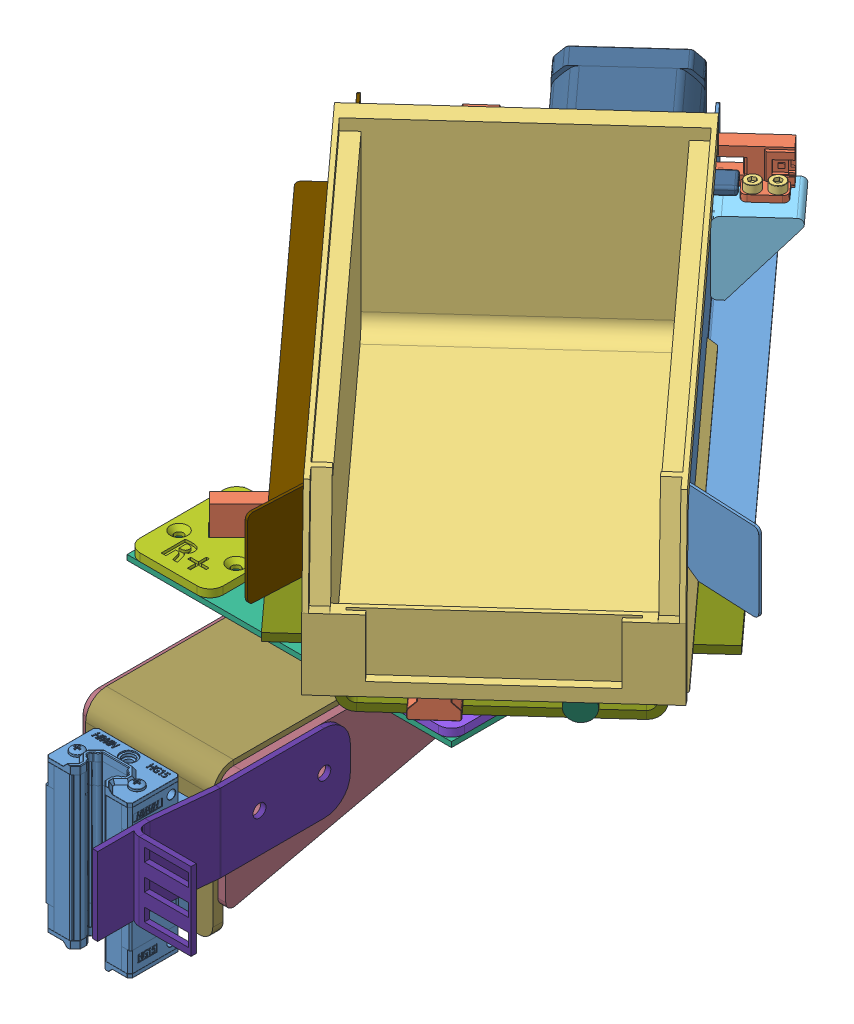
SolidWorks assembly T00003-000-R01, configuration Default. Lengths in mm.
Overall size (264.26 185.95 323.84).
38 component instances, 28 part files, 239 mates.
Components (placement in the parent):
- T00108-E00-R00-3: T00108-E00-R00 [Default] at (157.9488 862.2474 269.7743) x (1 0 0) z (0 1 0) size (34 23.7 61.49)
- T00110-E00-R00-1: T00110-E00-R00 [HGR15R400CE20] at (232.0778 918.7474 206.0743) x (0.739937 0 -0.672676) z (0.672676 0 0.739937) size (15 15 270)
- T00108-E00-R00-4: T00108-E00-R00 [Default] at (95.9442 919.5474 56.3288) x (0.739937 0 -0.672676) z (0.672676 0 0.739937) size (34 23.7 61.49)
- T00148-E00-R00-1: T00148-E00-R00 [Default] at (105.2918 941.2474 117.7314) x (0.739937 0 -0.672676) z (0.672676 0 0.739937) size (104.77 76.2 187.32)
- T00126-000-R00-1: T00126-000-R00 [Default] at (95.9442 950.5474 56.3288) x (0.739937 0 -0.672676) z (0 1 0) size (75 74 94)
- T00127-E00-R00-1: T00127-E00-R00 [DIN 625 - 6002 - 12,SI,NC,12_68] at (157.9488 901.2474 97.7743) x (0 1 0) z (0 0 1) size (9 32 32)
- T00128-0A4-R00-1: T00128-0A4-R00 [Default] at (157.9488 887.7474 97.7743) x (1 0 0) z (0 -1 0) size (25 25 21)
- T00129-E00-R00-1: T00129-E00-R00 [Circlip DIN 471 - 15 x 1.5] at (157.9488 905.9474 97.7743) x (0.837169 0 0.546944) z (0 -1 0) size (17.74 21.49 1.5)
- T00130-0A4-R01-1: T00130-0A4-R01 [Default] at (157.9488 895.7474 97.7743) x (0.672676 0 0.739937) z (0 -1 0) size (90 90 20)
- T00132-E00-R00-4: T00132-E00-R00 [Metric - Spur gear 1M 60T 20PA 9FW ---S60N75H50L42N] at (157.9488 896.7474 97.7743) x (0 1 0) z (0 0 1) size (9 61.95 61.95)
- T00107-E00-R00-1: T00107-E00-R00 [Varsayılan] at (157.9488 879.7474 61.7743) x (-1 0 0) z (0 1 0) size (42 58.5 65.65)
- T00131-E00-R00-2: T00131-E00-R00 [Metric - Spur gear 1M 12T 20PA 8FW ---S12O10H14L5N] at (157.9488 896.7474 61.7743) x (0 1 0) z (0.924225 0 0.381849) size (14 13.61 13.61)
- T00133-0A4-R00-3: T00133-0A4-R00 [Default] at (157.9488 862.2474 237.7743) x (1 0 0) z (0 1 0) size (49 210 57)
- T00134-DXF-R00-1: T00134-DXF-R00 [Default] at (130.4488 892.7474 239.7743) x (0 0 -1) z (-1 0 0) size (155 44.25 3)
- T00134-DXF-R00-2: T00134-DXF-R00 [Default] at (182.4488 892.7474 239.7743) x (0 0 -1) z (-1 0 0) size (155 44.25 3)
- T00105-E00-R00-1: T00105-E00-R00 [Default] at (142.4488 890.7474 46.2743) x (1 0 0) z (0 -1 0) size (6 6 11)
- T00105-E00-R00-2: T00105-E00-R00 [Default] at (173.4488 890.7474 46.2743) x (0.974973 0 -0.222324) z (0 -1 0) size (6 6 11)
- T00105-E00-R00-3: T00105-E00-R00 [Default] at (142.4488 890.7474 77.2743) x (1 0 0) z (0 -1 0) size (6 6 11)
- T00105-E00-R00-4: T00105-E00-R00 [Default] at (173.4488 890.7474 77.2743) x (1 0 0) z (0 -1 0) size (6 6 11)
- T00107-E00-R00-2: T00107-E00-R00 [Varsayılan] at (107.666 933.2474 9.0154) x (-0.739937 0 0.672676) z (0.672676 0 0.739937) size (42 58.5 65.65)
- T00111-E00-R00-1: T00111-E00-R00 [Default] at (270.4537 933.2474 188.0801) x (-0.427706 0.816015 0.388828) z (-0.603799 -0.578031 0.548914) size (10 240 10)
- T00135-DXF-R01-1: T00135-DXF-R01 [Default] at (168.0389 918.7474 108.8734) x (-0.672676 0 -0.739937) z (0.739937 0 -0.672676) size (219 39 131)
- T00136-DXF-R01-1: T00136-DXF-R01 [Default] at (187.4488 877.7474 233.7743) x (0 0 -1) z (1 0 0) size (94.88 30 25)
- T00137-000-R00-1: T00137-000-R00 [gespiegeld] at (182.1991 941.2474 198.0361) x (0.672676 0 0.739937) z (-0.739937 0 0.672676) size (201.93 32 21.92)
- T00138-000-R00-1: T00138-000-R00 [gespiegeld] at (254.7129 941.2474 132.1138) x (0.672676 0 0.739937) z (-0.739937 0 0.672676) size (201.93 32 21.92)
- T00153-E00-R00-4: T00153-E00-R00 [Default] at (161.4127 977.2474 25.0247) x (-0.672676 0 -0.739937) z (0 1 0) size (13 22.4 13.7)
- socket head cap screw_iso-1: socket head cap screw_iso [ISO 4762 M3 x 16 - 16N] at (172.7808 978.7474 24.1502) x (0 -1 0) z (0.997971 0 0.063667) size (19 5.5 5.5)
- hex nut style 1 gradeab_iso-1: hex nut style 1 gradeab_iso [ISO - 4032 - M3 - W - N] at (172.7808 965.2474 24.1502) x (1 0 0) z (0 1 0) size (5.5 6.35 2.4)
- socket head cap screw_iso-2: socket head cap screw_iso [ISO 4762 M3 x 16 - 16N] at (177.9604 978.7474 19.4415) x (0 -1 0) z (0 0 1) size (19 5.5 5.5)
- hex nut style 1 gradeab_iso-3: hex nut style 1 gradeab_iso [ISO - 4032 - M3 - W - N] at (177.9604 965.4397 19.4415) x (0.95019 0 0.311672) z (0 1 0) size (5.5 6.35 2.4)
- T00153-E00-R00-7: T00153-E00-R00 [Default] at (120.7549 900.9974 152.459) x (0.707107 0 0.707107) z (0 1 0) size (13 22.4 13.7)
- T00153-E00-R00-8: T00153-E00-R00 [Default] at (195.1426 900.9974 152.459) x (0.707107 0 -0.707107) z (0 1 0) size (13 22.4 13.7)
- T00168-03D-R00-2: T00168-03D-R00 [Default] at (164.6415 959.2474 31.5496) x (-0.672676 0 -0.739937) z (0.739937 0 -0.672676) size (20 28 25.65)
- T00161-0A4-R00-2: T00161-0A4-R00 [Default] at (157.9488 894.7474 165.2743) size (125 2 45)
- T00164-03D-R00-1: T00164-03D-R00 [Default] at (157.9488 896.7474 165.2743) x (1 0 0) z (0 1 0) size (32 42.2 3)
- T00165-03D-R00-1: T00165-03D-R00 [Default] at (250.9488 896.7474 165.2743) x (1 0 0) z (0 1 0) size (32 42.2 3)
- T00162-03D-R02-1: T00162-03D-R02 [Default] at (191.5826 915.7474 134.7711) x (0.739937 0 -0.672676) z (0 -1 0) size (28 24.69 13.5)
- T00163-03D-R01-1: T00163-03D-R01 [Default] at (159.0073 970.5474 55.084) x (0.739937 0 -0.672676) z (0 1 0) size (38 30 18.2)
Mates (geometry in assembly coordinates):
- Coincident1: coincident: plane of ? through (170.4488 216.5018 364.6743) normal (1 0 0); plane of ? through (170.4488 228.5018 34.6743) normal (-1 0 0)
- Coincident2: coincident: plane of ? through (148.4488 238.5018 364.6743) normal (0 1 0); plane of ? through (170.4488 238.5018 394.6743) normal (0 1 0)
- Coincident3: coincident: plane of ? through (145.4488 216.5018 364.6743) normal (-1 0 0); plane of ? through (145.4488 223.5018 394.6743) normal (1 0 0)
- Coincident4: coincident: plane of ? through (148.4488 213.5018 364.6743) normal (0 -1 0); plane of ? through (142.4488 213.5018 34.6743) normal (0 -1 0)
- Coincident5: coincident: plane of ? through (142.4488 228.5018 404.6743) normal (0 0 1); plane of ? through (170.4488 223.5018 404.6743) normal (0 0 1)
- Width1: width: plane of ? through (142.4488 228.5018 404.6743) normal (0 0 1); plane of ? through (142.4488 228.5018 24.6743) normal (0 0 -1); plane of ? through (148.4488 216.5018 64.6743) normal (0 0 -1); plane of ? through (148.4488 216.5018 364.6743) normal (0 0 1)
- Concentric1: concentric: cylinder of ? through (142.4488 226.0018 394.6743) axis (1 0 0) radius 3.25; cylinder of ? through (157.9488 226.0018 394.6743) axis (-1 0 0) radius 3
- Concentric2: concentric: cylinder of ? through (142.4488 226.0018 34.6743) axis (1 0 0) radius 3.25; cylinder of ? through (157.9488 226.0018 34.6743) axis (-1 0 0) radius 3
- Width2: width: plane of ? through (168.9488 223.0018 34.6743) normal (1 0 0); plane of ? through (146.9488 219.0018 34.6743) normal (-1 0 0); plane of ? through (145.4488 223.5018 394.6743) normal (1 0 0); plane of ? through (170.4488 228.5018 34.6743) normal (-1 0 0)
- Width3: width: plane of ? through (168.9488 223.0127 394.9296) normal (1 0 0); plane of ? through (146.9488 219.0272 395.2699) normal (-1 0 0); plane of ? through (142.4488 223.5018 394.6743) normal (-1 0 0); plane of ? through (173.4488 228.5018 34.6743) normal (1 0 0)
- Tangent1: tangent: cylinder of ? through (157.9488 226.0018 -111.0344) axis (-1 0 0) radius 25; plane of ? through (135.9488 201.0018 1171.0489) normal (0 1 0)
- Tangent2: tangent: cylinder of ? through (157.9488 226.0018 -471.0344) axis (-1 0 0) radius 25; plane of ? through (135.9488 201.0018 1171.0489) normal (0 1 0)
- Width4: width: plane of ? through (173.4488 228.5018 -471.0344) normal (1 0 0); plane of ? through (142.4488 223.5018 -111.0344) normal (-1 0 0); plane of ? through (179.9488 201.0018 1171.0489) normal (-1 0 0); plane of ? through (135.9488 201.0018 1171.0489) normal (1 0 0)
- Width9: width: plane of ? through (172.9488 242.5018 314.4743) normal (1 0 0); plane of ? through (142.9488 242.5018 274.8743) normal (-1 0 0); plane of ? through (142.4488 223.5018 394.6743) normal (-1 0 0); plane of ? through (173.4488 228.5018 34.6743) normal (1 0 0)
- Coincident16: coincident: plane of ? through (148.1488 242.5018 269.6743) normal (0 0 -1); plane of ? through (150.9488 242.5018 269.6743) normal (0 0 1)
- Width10: width: plane of ? through (150.4488 833.0474 258.1086) normal (1 0 0); plane of ? through (165.4488 833.0474 258.1086) normal (-1 0 0); plane of ? through (150.4488 242.5018 258.0086) normal (-1 0 0); plane of ? through (165.4488 242.5018 258.0086) normal (1 0 0)
- Coincident18: coincident: plane of ? through (152.9073 834.5474 254.6743) normal (0 0 1); plane of ? through (162.9488 242.5018 254.6743) normal (0 0 -1)
- Width11: width: plane of ? through (172.9488 242.5018 314.4743) normal (1 0 0); plane of ? through (142.9488 242.5018 274.8743) normal (-1 0 0); plane of ? through (150.4488 242.5018 269.1743) normal (-1 0 0); plane of ? through (165.4488 242.5018 269.1743) normal (1 0 0)
- Coincident23: coincident: plane of T00110-E00-R00-1; plane of ? through (70.8326 930.4131 121.9122) normal (0.01567 0 -0.999877)
- Coincident24: coincident: plane of T00110-E00-R00-1 through (17.7623 933.7474 108.579) normal (0 1 0); plane of ? through (70.8718 933.7474 119.4125) normal (0 -1 0)
- Concentric5: concentric: circle of ?; cylinder of T00126-000-R00-1 through (87.3518 946.5474 101.6686) axis (0 1 0) radius 2.25
- Concentric6: concentric: circle of ?; cylinder of T00126-000-R00-1 through (86.9444 946.5474 127.6654) axis (0 1 0) radius 2.25
- Concentric8: concentric: cylinder of T00127-E00-R00-1 through (157.9488 880.6099 97.7743) axis (0 1 0) radius 7.5; cylinder of T00128-0A4-R00-1 through (157.9488 887.7474 97.7743) axis (0 -1 0) radius 7.5
- Coincident29: coincident: plane of T00127-E00-R00-1 through (147.8988 896.7474 97.7743) normal (0 -1 0); plane of T00128-0A4-R00-1 through (167.9488 896.7474 97.7743) normal (0 1 0)
- Concentric9: concentric: cylinder of T00128-0A4-R00-1 through (157.9488 887.7474 97.7743) axis (0 -1 0) radius 7.15; cylinder of T00129-E00-R00-1 through (157.9488 907.4474 97.7743) axis (0 -1 0) radius 7.15
- Coincident30: coincident: plane of T00128-0A4-R00-1 through (165.4488 905.9474 97.7743) normal (0 1 0); plane of T00129-E00-R00-1 through (157.9488 905.9474 97.7743) normal (0 -1 0)
- Concentric10: concentric: cylinder of T00127-E00-R00-1 through (157.9488 880.6099 97.7743) axis (0 1 0) radius 16; cylinder of T00130-0A4-R01-1 through (157.9488 895.7474 97.7743) axis (0 1 0) radius 16
- Coincident31: coincident: plane of T00127-E00-R00-1 through (142.2488 905.7474 97.7743) normal (0 1 0); plane of T00130-0A4-R01-1 through (168.7116 905.7474 109.6133) normal (0 -1 0)
- Concentric11: concentric: cylinder of T00130-0A4-R01-1 through (157.9488 895.7474 97.7743) axis (0 1 0) radius 21; cylinder of T00132-E00-R00-4 through (157.9488 946.7475 97.7743) axis (0 -1 0) radius 21
- Coincident32: coincident: plane of T00130-0A4-R01-1 through (172.075 905.7474 113.313) normal (0 -1 0); plane of T00132-E00-R00-4 through (157.9488 905.7474 97.7743) normal (0 1 0)
- Concentric12: concentric: cylinder of T00107-E00-R00-1 through (157.9488 904.7474 61.7743) axis (0 -1 0) radius 2.5; cylinder of T00131-E00-R00-2 through (157.9488 910.7475 61.7743) axis (0 -1 0) radius 2.5
- Coincident33: coincident: plane of T00107-E00-R00-1 through (159.9488 904.7474 61.7743) normal (0 1 0); plane of T00131-E00-R00-2 through (157.9488 904.7474 61.7743) normal (0 1 0)
- Distance5: distance = 1 mm: plane of T00131-E00-R00-2 through (157.9488 904.7474 61.7743) normal (0 1 0); plane of T00130-0A4-R01-1 through (172.075 905.7474 113.313) normal (0 -1 0)
- Coincident34: coincident: plane of T00108-E00-R00-3 through (173.9488 881.9474 241.7743) normal (0 0 -1); plane of T00133-0A4-R00-3 through (157.9488 862.2474 241.7743) normal (0 0 1)
- Concentric13: concentric: cylinder of T00108-E00-R00-3 through (144.9488 875.2474 241.7743) axis (0 0 -1) radius 1.65; cylinder of T00133-0A4-R00-3 through (144.9488 875.2474 241.7743) axis (0 0 -1) radius 2
- Concentric14: concentric: circle of T00108-E00-R00-3; cylinder of T00133-0A4-R00-3 through (170.9488 849.2474 241.7743) axis (0 0 -1) radius 2
- Coincident35: coincident: plane of T00128-0A4-R00-1 through (170.4488 890.7474 97.7743) normal (0 1 0); plane of T00133-0A4-R00-3 through (157.9488 890.7474 237.7743) normal (0 -1 0)
- Concentric15: concentric: cylinder of T00128-0A4-R00-1 through (157.9488 887.7474 97.7743) axis (0 -1 0) radius 12.5; cylinder of T00133-0A4-R00-3 through (157.9488 900.7474 97.7743) axis (0 -1 0) radius 10
- Concentric16: concentric: cone of T00107-E00-R00-1 through (142.4488 879.7474 46.2743) axis (0 -1 0); cylinder of T00133-0A4-R00-3 through (142.4488 894.7474 46.2743) axis (0 -1 0) radius 1.75
- Concentric17: concentric: circle of T00107-E00-R00-1; cylinder of T00133-0A4-R00-3 through (173.4488 894.7474 77.2743) axis (0 -1 0) radius 1.75
- Distance6: distance = 2 mm: plane of T00134-DXF-R00-2 through (185.4488 892.7474 233.7743) normal (0 1 0); plane of T00133-0A4-R00-3 through (157.9488 894.7474 237.7743) normal (0 1 0)
- Distance7: distance = 2 mm: plane of T00133-0A4-R00-3 through (157.9488 862.2474 241.7743) normal (0 0 1); plane of T00134-DXF-R00-2 through (185.4488 851.5004 239.7743) normal (0 0 1)
- Coincident39: coincident: plane of T00133-0A4-R00-3 through (182.4488 894.7474 31.7743) normal (1 0 0); plane of T00134-DXF-R00-2 through (182.4488 886.7474 233.7743) normal (-1 0 0)
- Coincident40: coincident: plane of T00133-0A4-R00-3 through (133.4488 894.7474 237.7743) normal (-1 0 0); plane of T00134-DXF-R00-1 through (133.4488 886.7474 233.7743) normal (1 0 0)
- Distance8: distance = 2 mm: plane of T00134-DXF-R00-1 through (133.4488 851.5004 239.7743) normal (0 0 1); plane of T00133-0A4-R00-3 through (157.9488 862.2474 241.7743) normal (0 0 1)
- Distance9: distance = 2 mm: plane of T00133-0A4-R00-3 through (157.9488 894.7474 237.7743) normal (0 1 0); plane of T00134-DXF-R00-1 through (133.4488 892.7474 233.7743) normal (0 1 0)
- Concentric18: concentric: cylinder of T00133-0A4-R00-3 through (173.4488 894.7474 46.2743) axis (0 -1 0) radius 1.75; cylinder of T00105-E00-R00-2 through (173.4488 879.7474 46.2743) axis (0 1 0) radius 1.75
- Coincident43: coincident: plane of T00107-E00-R00-1 through (157.9488 879.7474 61.7743) normal (0 1 0); plane of T00105-E00-R00-2 through (173.4488 879.7474 46.2743) normal (0 -1 0)
- Coincident44: coincident: plane of T00133-0A4-R00-3 through (157.9488 890.7474 237.7743) normal (0 -1 0); plane of T00105-E00-R00-1 through (142.4488 890.7474 46.2743) normal (0 1 0)
- Concentric19: concentric: cylinder of T00133-0A4-R00-3 through (142.4488 894.7474 46.2743) axis (0 -1 0) radius 1.75; cylinder of T00105-E00-R00-1 through (142.4488 879.7474 46.2743) axis (0 1 0) radius 1.75
- Coincident45: coincident: plane of T00133-0A4-R00-3 through (157.9488 890.7474 237.7743) normal (0 -1 0); plane of T00105-E00-R00-3 through (142.4488 890.7474 77.2743) normal (0 1 0)
- Concentric20: concentric: cylinder of T00133-0A4-R00-3 through (142.4488 894.7474 77.2743) axis (0 -1 0) radius 1.75; cylinder of T00105-E00-R00-3 through (142.4488 879.7474 77.2743) axis (0 1 0) radius 1.75
- Coincident46: coincident: plane of T00133-0A4-R00-3 through (157.9488 890.7474 237.7743) normal (0 -1 0); plane of T00105-E00-R00-4 through (173.4488 890.7474 77.2743) normal (0 1 0)
- Concentric21: concentric: cylinder of T00133-0A4-R00-3 through (173.4488 894.7474 77.2743) axis (0 -1 0) radius 1.75; cylinder of T00105-E00-R00-4 through (173.4488 879.7474 77.2743) axis (0 1 0) radius 1.75
- Coincident49: coincident: plane of T00110-E00-R00-1 through (55.2648 921.8332 1.9189) normal (-0.672676 0 -0.739937); plane of T00107-E00-R00-2 through (80.4226 933.2474 -20.9521) normal (-0.672676 0 -0.739937)
- Concentric22: concentric: cylinder of T00107-E00-R00-2 through (124.4829 933.2474 27.5138) axis (-0.672676 0 -0.739937) radius 2.5; cylinder of T00111-E00-R00-1 through (129.1917 933.2474 32.6934) axis (-0.672676 0 -0.739937) radius 2.5
- Coincident51: coincident: plane of T00107-E00-R00-2 through (109.0114 933.2474 10.4952) normal (0.672676 0 0.739937); plane of T00111-E00-R00-1 through (109.0114 933.2474 10.4952) normal (-0.672676 0 -0.739937)
- Coincident52: coincident: plane of T00130-0A4-R01-1 through (188.2192 915.7474 131.0715) normal (0 1 0); plane of T00135-DXF-R01-1 through (168.0389 915.7474 108.8734) normal (0 -1 0)
- Coincident53: coincident: plane of T00110-E00-R00-1 through (45.2756 918.7474 11.0001) normal (0 -1 0); plane of T00135-DXF-R01-1 through (168.0389 918.7474 108.8734) normal (0 1 0)
- Distance11: distance = 3 mm: plane of T00107-E00-R00-2 through (107.666 933.2474 9.0154) normal (0.672676 0 0.739937); plane of T00135-DXF-R01-1 through (93.0355 918.7474 26.3704) normal (-0.672676 0 -0.739937)
- Concentric23: concentric: cylinder of T00107-E00-R00-2 through (119.1351 948.7474 -1.4111) axis (0.672676 0 0.739937) radius 1.25; cylinder of T00135-DXF-R01-1 through (268.4692 948.7474 162.8549) axis (-0.672676 0 -0.739937) radius 1.75
- Concentric24: concentric: cylinder of T00107-E00-R00-2 through (96.197 948.7474 19.4419) axis (0.672676 0 0.739937) radius 1.25; cylinder of T00135-DXF-R01-1 through (245.5312 948.7474 183.7078) axis (-0.672676 0 -0.739937) radius 1.75
- Coincident55: coincident: plane of T00148-E00-R00-1 through (231.3009 941.2474 256.3401) normal (0 -1 0); plane of T00135-DXF-R01-1 through (168.0389 941.2474 108.8734) normal (0 1 0)
- Width12: width: plane of T00148-E00-R00-1 through (178.402 941.2474 51.267) normal (0.739937 0 -0.672676); plane of T00148-E00-R00-1 through (109.7085 941.2474 113.7162) normal (-0.739937 0 0.672676); plane of T00135-DXF-R01-1 through (49.2784 941.2474 75.6103) normal (-0.739937 0 0.672676); plane of T00135-DXF-R01-1 through (146.2101 941.2474 -12.5103) normal (0.739937 0 -0.672676)
- Coincident56: coincident: plane of T00148-E00-R00-1 through (106.4871 1014.7804 119.0477) normal (0.672676 0 0.739937); plane of T00126-000-R00-1 through (131.9324 950.5474 95.9154) normal (-0.672676 0 -0.739937)
- Coincident62: coincident: plane of ? through (148.4488 238.5018 364.6743) normal (0 1 0); plane of ? through (100.4488 238.5018 294.6743) normal (0 -1 0)
- Width15: width: plane of ? through (142.9488 242.5018 224.6743) normal (-1 0 0); plane of ? through (172.9488 242.5018 364.6743) normal (1 0 0); plane of ? through (142.4488 223.5018 394.6743) normal (-1 0 0); plane of ? through (173.4488 228.5018 34.6743) normal (1 0 0)
- Coincident63: coincident: plane of ? through (148.4488 216.5018 364.6743) normal (0 0 1); plane of ? through (57.9488 242.5018 364.6743) normal (0 0 1)
- Width16: width: plane of ? through (57.9488 242.5018 364.6743) normal (0 0 1); plane of ? through (57.9488 242.5018 224.6743) normal (0 0 -1); plane of ? through (148.1488 242.5018 269.6743) normal (0 0 -1); plane of ? through (167.7488 242.5018 319.6743) normal (0 0 1)
- Coincident64: coincident: plane of ? through (164.4488 242.5018 266.5885) normal (0 -1 0); plane of ? through (100.4488 242.5018 294.6743) normal (0 1 0)
- Coincident65: coincident: plane of ? through (167.7488 242.5018 314.4743) normal (0 -1 0); plane of ? through (100.4488 242.5018 294.6743) normal (0 1 0)
- Coincident70: coincident: plane of ? through (82.9488 242.5018 294.6743) normal (0 -1 0); plane of ? through (100.4488 242.5018 294.6743) normal (0 1 0)
- Concentric28: concentric: cylinder of ? through (82.9488 248.5018 339.6743) axis (0 1 0) radius 6; cylinder of ? through (82.9488 242.5018 339.6743) axis (0 -1 0) radius 6.25
- Concentric29: concentric: cylinder of ? through (82.9488 248.5018 249.6743) axis (0 1 0) radius 6; cylinder of ? through (82.9488 242.5018 249.6743) axis (0 -1 0) radius 6.25
- Coincident74: coincident: plane of T00130-0A4-R01-1 through (157.9488 895.7474 97.7743) normal (-0.739937 0 0.672676); plane of T00135-DXF-R01-1 through (168.0389 918.7474 108.8734) normal (0.739937 0 -0.672676)
- Distance14: distance = 15 mm: plane of T00135-DXF-R01-1 through (168.0389 918.7474 108.8734) normal (-0.672676 0 -0.739937); plane of T00130-0A4-R01-1 through (157.9488 895.7474 97.7743) normal (0.672676 0 0.739937)
- LimitDistance1: limit distance = 51.7728 mm: plane of ? through (69.531 925.1631 109.2402) normal (-0.999877 0 -0.01567); plane of T00110-E00-R00-1
- LimitAngle1: limit planar angle = 0 rad: plane of T00135-DXF-R01-1 through (134.3718 918.7474 139.4801) normal (-0.739937 0 0.672676); plane of T00133-0A4-R00-3 through (133.4488 894.7474 31.7743) normal (0 0 -1)
- LimitDistance2: limit distance = 589.0457 mm: plane of ? through (100.4488 242.5018 294.6743) normal (0 1 0); plane of ? through (163.0988 831.5474 263.3586) normal (0 -1 0)
- LimitDistance3: limit distance = 1272.0833 mm: plane of ? through (170.4488 223.5018 -101.0344) normal (0 0 1); plane of ? through (157.9488 198.0018 1171.0489) normal (0 0 1)
- Coincident103: coincident: plane of ? through (132.9488 198.0018 1171.0489) normal (-1 0 0); plane of ? through (132.9488 203.0018 1171.0489) normal (-1 0 0)
- Coincident104: coincident: plane of ? through (157.9488 198.0018 1171.0489) normal (0 0 1); plane of ? through (137.9488 203.0018 1171.0489) normal (0 0 -1)
- Coincident105: coincident: plane of ? through (132.9488 198.0018 1171.0489) normal (0 -1 0); plane of ? through (137.9488 198.0018 1171.0489) normal (0 -1 0)
- Coincident106: coincident: plane of ? through (132.9488 198.0018 1171.0489) normal (-1 0 0); plane of ? through (132.9488 203.0018 -564.9511) normal (-1 0 0)
- Coincident107: coincident: plane of ? through (157.9488 198.0018 -560.9511) normal (0 0 -1); plane of ? through (137.9488 203.0018 -560.9511) normal (0 0 1)
- Coincident108: coincident: plane of ? through (132.9488 198.0018 1171.0489) normal (0 -1 0); plane of ? through (137.9488 198.0018 -564.9511) normal (0 -1 0)
- Distance26: distance = 1 mm: plane of ? through (117.9488 237.5018 249.6743) normal (0 1 0); plane of ? through (100.4488 238.5018 294.6743) normal (0 -1 0)
- Concentric55: concentric: circle of ?; cylinder of ? through (112.9488 234.0018 249.6743) axis (0 1 0) radius 11
- Coincident125: coincident: plane of ? through (123.9488 230.5018 249.6743) normal (0 -1 0); plane of ? through (117.9488 230.5018 249.6743) normal (0 1 0)
- Concentric56: concentric: cylinder of ? through (112.9488 234.0018 249.6743) axis (0 1 0) radius 11; cylinder of ? through (112.9488 227.0018 249.6743) axis (0 1 0) radius 11
- Distance27: distance = 1 mm: plane of ? through (108.7629 237.5018 336.9396) normal (0 1 0); plane of ? through (100.4488 238.5018 294.6743) normal (0 -1 0)
- Concentric57: concentric: cylinder of ? through (112.9488 242.5018 339.6743) axis (0 -1 0) radius 4.25; cylinder of ? through (112.9488 234.0018 339.6743) axis (0 -1 0) radius 11
- Coincident127: coincident: plane of ? through (108.7629 230.5018 336.9396) normal (0 -1 0); plane of ? through (103.7399 230.5018 333.6579) normal (0 1 0)
- Concentric58: concentric: cylinder of ? through (112.9488 234.0018 339.6743) axis (0 -1 0) radius 11; cylinder of ? through (112.9488 227.0018 339.6743) axis (0 -1 0) radius 11
- Concentric59: concentric: cylinder of ? through (82.9488 208.9018 -211.0344) axis (0 1 0) radius 7.5; cylinder of ? through (82.9488 1416.5905 -211.0344) axis (0 1 0) radius 7.5
- Distance28: distance = 1 mm: plane of ? through (105.5523 237.5018 -196.2669) normal (0 1 0); plane of ? through (100.4488 238.5018 -211.0344) normal (0 -1 0)
- Coincident133: coincident: plane of T00134-DXF-R00-2 through (185.4488 892.7474 233.7743) normal (0 1 0); plane of T00136-DXF-R01-1 through (185.4488 892.7474 273.7743) normal (0 1 0)
- Coincident134: coincident: plane of T00134-DXF-R00-2 through (185.4488 886.7474 233.7743) normal (1 0 0); plane of T00136-DXF-R01-1 through (185.4488 877.7474 233.7743) normal (-1 0 0)
- Concentric63: concentric: cylinder of T00134-DXF-R00-2 through (175.4488 877.7474 203.7743) axis (1 0 0) radius 2.75; cylinder of T00136-DXF-R01-1 through (185.4488 877.7474 203.7743) axis (1 0 0) radius 2.5
- Coincident135: coincident: plane of ? through (172.9488 242.5018 314.4743) normal (1 0 0); plane of ? through (172.9488 266.0484 296.2234) normal (-1 0 0)
- Concentric68: concentric: cylinder of ? through (209.3488 260.2518 294.6743) axis (1 0 0) radius 6; cylinder of ? through (-989.14 260.2518 294.6743) axis (-1 0 0) radius 7.5
- Distance33: distance = 17 mm: plane of ? through (189.9488 282.6397 279.5818) normal (-1 0 0); plane of ? through (172.9488 242.5018 314.4743) normal (1 0 0)
- Lock1: lock: unknown of ?; unknown of ?
- Coincident136: coincident: plane of T00110-E00-R00-1 through (45.2756 918.7474 11.0001) normal (0 -1 0); plane of T00135-DXF-R01-1 through (168.0389 918.7474 108.8734) normal (0 1 0)
- Concentric77: concentric: cylinder of T00126-000-R00-1 through (146.4283 933.2474 51.6534) axis (-0.672676 0 -0.739937) radius 5.25; cylinder of T00111-E00-R00-1 through (109.0114 933.2474 10.4952) axis (0.672676 0 0.739937) radius 5
- Coincident137: coincident: plane of T00135-DXF-R01-1 through (168.0389 941.2474 108.8734) normal (0 1 0); plane of T00137-000-R00-1 through (182.1991 941.2474 198.0361) normal (0 -1 0)
- Distance34: distance = 1 mm: plane of T00135-DXF-R01-1 through (49.2784 941.2474 75.6103) normal (-0.739937 0 0.672676); plane of T00137-000-R00-1 through (48.5384 941.2474 76.2829) normal (-0.739937 0 0.672676)
- Distance35: distance = 32 mm: plane of T00137-000-R00-1 through (169.6202 941.2474 209.4716) normal (0.672676 0 0.739937); plane of T00135-DXF-R01-1 through (191.8858 941.2474 232.4769) normal (0.672676 0 0.739937)
- Coincident140: coincident: plane of T00135-DXF-R01-1 through (168.0389 941.2474 108.8734) normal (0 1 0); plane of T00138-000-R00-1 through (254.7129 941.2474 132.1138) normal (0 -1 0)
- Distance36: distance = 1 mm: plane of T00135-DXF-R01-1 through (146.2101 941.2474 -12.5103) normal (0.739937 0 -0.672676); plane of T00138-000-R00-1 through (146.95 941.2474 -13.183) normal (0.739937 0 -0.672676)
- Distance37: distance = 32 mm: plane of T00138-000-R00-1 through (268.0318 941.2474 120.0056) normal (0.672676 0 0.739937); plane of T00135-DXF-R01-1 through (288.8175 941.2474 144.3563) normal (0.672676 0 0.739937)
- Concentric78: concentric: circle of T00108-E00-R00-4; cylinder of T00126-000-R00-1 through (96.8186 947.5474 37.9648) axis (0 1 0) radius 2.25
- Concentric80: concentric: circle of T00108-E00-R00-4; cylinder of T00126-000-R00-1 through (95.0698 947.5474 74.6927) axis (0 1 0) radius 2.25
- Coincident142: coincident: plane of T00108-E00-R00-4 through (121.0349 947.5474 60.1427) normal (0 1 0); plane of T00126-000-R00-1 through (95.9442 947.5474 56.3288) normal (0 -1 0)
- Width17: width: plane of T00108-E00-R00-4 through (72.7874 925.9631 37.9178) normal (0.739937 0 -0.672676); plane of T00108-E00-R00-4 through (79.8168 925.9631 31.5274) normal (-0.739937 0 0.672676); plane of T00110-E00-R00-1 through (44.9057 919.2474 11.3364) normal (-0.739937 0 0.672676); plane of T00110-E00-R00-1 through (56.0047 919.2474 1.2463) normal (0.739937 0 -0.672676)
- Concentric81: concentric: circle of T00108-E00-R00-3; cylinder of T00133-0A4-R00-3 through (144.9488 875.2474 241.7743) axis (0 0 -1) radius 2
- Concentric82: concentric: circle of T00108-E00-R00-3; cylinder of T00133-0A4-R00-3 through (170.9488 849.2474 241.7743) axis (0 0 -1) radius 2
- Coincident144: coincident: plane of T00108-E00-R00-3 through (173.9488 881.9474 241.7743) normal (0 0 -1); plane of T00133-0A4-R00-3 through (157.9488 862.2474 241.7743) normal (0 0 1)
- Coincident145: coincident: plane of T00136-DXF-R01-1 through (182.9675 877.7474 233.6502) normal (-1 0 0); circle of ?
- Parallel1: parallel: line of T00136-DXF-R01-1 through (184.9675 892.7474 303.6502) axis (0 0 -1); line of ? through (182.9675 887.2474 281.5502) axis (0 0 1)
- Width18: width: plane of T00136-DXF-R01-1 through (184.9675 892.7474 303.6502) normal (0 0 1); plane of T00136-DXF-R01-1 through (184.9675 877.7474 275.6502) normal (0 0 1); plane of ? through (184.4675 900.2474 300.8502) normal (0 0 1); plane of ? through (180.7675 900.2474 278.4502) normal (0 0 -1)
- Distance38: distance = 1 mm: plane of ? through (182.0675 893.7474 286.7502) normal (0 -1 0); plane of T00136-DXF-R01-1 through (187.9675 892.7474 270.6502) normal (0 1 0)
- Coincident146: coincident: plane of T00136-DXF-R01-1 through (184.9675 877.7474 233.7743) normal (1 0 0); plane of ? through (184.9675 879.8974 301.3502) normal (-1 0 0)
- Distance39: distance = 19 mm: plane of T00136-DXF-R01-1 through (184.9675 877.7474 275.6502) normal (0 0 1); moEndPointRef_w of ?
- Parallel2: parallel: line of T00136-DXF-R01-1 through (184.9675 862.7474 303.6502) axis (0 1 0); line of ? through (184.9675 889.0974 301.3502) axis (0 -1 0)
- Width19: width: plane of T00136-DXF-R01-1 through (187.9675 862.7474 270.6502) normal (0 -1 0); plane of T00136-DXF-R01-1 through (187.9675 892.7474 270.6502) normal (0 1 0); plane of ? through (190.9675 889.0974 287.9502) normal (0 1 0); plane of ? through (187.4675 866.3974 301.3502) normal (0 -1 0)
- Coincident147: coincident: plane of T00133-0A4-R00-3 through (157.9488 894.7474 237.7743) normal (0 1 0); plane of ? through (132.9488 894.7474 61.7743) normal (0 -1 0)
- Width20: width: plane of T00133-0A4-R00-3 through (182.4488 894.7474 31.7743) normal (1 0 0); plane of T00133-0A4-R00-3 through (133.4488 894.7474 237.7743) normal (-1 0 0); plane of ? through (182.9488 894.7474 61.7743) normal (-1 0 0); plane of ? through (132.9488 894.7474 61.7743) normal (1 0 0)
- Coincident148: coincident: plane of T00133-0A4-R00-3 through (133.4488 894.7474 31.7743) normal (0 0 -1); plane of ? through (157.9488 894.7474 31.7743) normal (0 0 -1)
- InPlace1: in place: plane of ? through (178.9488 905.7474 97.7743) normal (0 -1 0); plane of ? through (0 905.7474 0) normal (0 -1 0); moOrthogonalPlaneRef_w of ? through (178.9488 905.7474 97.7743) normal (0 -1 0); plane of ? through (0 905.7474 0) normal (0 0 -1); plane of ? through (178.9488 905.7474 97.7743) normal (0 -1 0); plane of ? through (0 905.7474 0) normal (-1 0 0); plane of ? through (144.1979 905.7474 113.6461) normal (0 -1 0); unknown of ?
- Coincident153: coincident: plane of T00130-0A4-R01-1; plane of ?
- Coincident154: coincident: moOrthogonalPlaneRef_w of T00130-0A4-R01-1 through (157.9488 905.7474 97.7743) axis (-0.755798 0 -0.654804); plane of ? through (157.9488 905.7474 97.7743) normal (-0.755798 0 -0.654804)
- Coincident155: coincident: moOrthogonalPlaneRef_w of T00130-0A4-R01-1; plane of ? through (157.9488 905.7474 97.7743) normal (-0.654804 0 0.755798)
- Coincident156: coincident: plane of T00130-0A4-R01-1 through (168.0287 905.7474 116.197) normal (0 -1 0); plane of ? through (157.9488 905.7474 97.7743) normal (0 1 0)
- Concentric83: concentric: cylinder of T00130-0A4-R01-1 through (139.9489 905.7474 64.8767) axis (0 -1 0) radius 2.1; cylinder of ? through (139.9489 901.7474 64.8767) axis (0 1 0) radius 2.25
- Coincident157: coincident: plane of ?; plane of ?
- InPlace2: in place: plane of T00134-DXF-R00-2 through (185.4488 886.7474 233.7743) normal (1 0 0); plane of ? through (185.4488 0 0) normal (1 0 0); plane of T00134-DXF-R00-2 through (185.4488 886.7474 233.7743) normal (1 0 0); plane of ? through (185.4488 0 0) normal (0 1 0); plane of T00134-DXF-R00-2 through (185.4488 886.7474 233.7743) normal (1 0 0); plane of ? through (185.4488 0 0) normal (0 0 -1); plane of T00134-DXF-R00-2 through (185.4488 886.7474 233.7743) normal (1 0 0); unknown of ?
- Coincident165: coincident: plane of T00134-DXF-R00-2; plane of ?
- Coincident166: coincident: moOrthogonalPlaneRef_w of T00134-DXF-R00-2 through (185.4488 892.7474 239.7743) normal (0 -1 0); plane of ? through (185.4488 892.7474 239.7743) normal (0 -1 0)
- Coincident167: coincident: moOrthogonalPlaneRef_w of T00134-DXF-R00-2 through (185.4488 892.7474 239.7743) normal (0 0 -1); plane of ? through (185.4488 892.7474 239.7743) normal (0 0 1)
- Coincident173: coincident: plane of T00134-DXF-R00-2 through (185.4488 886.7474 233.7743) normal (1 0 0); plane of ? through (185.4488 890.7474 97.2743) normal (-1 0 0)
- Distance44: distance = 15 mm: plane of T00134-DXF-R00-2 through (185.4488 889.7474 84.7743) normal (0 0 -1); plane of ? through (185.4488 879.7474 69.7743) normal (0 0 -1)
- Coincident175: coincident: plane of T00134-DXF-R00-2 through (185.4488 892.7474 233.7743) normal (0 1 0); plane of ? through (212.9488 892.7474 97.2743) normal (0 1 0)
- Width21: width: plane of ? through (240.4488 892.7474 124.7743) normal (0 0 1); plane of ? through (240.4488 892.7474 69.7743) normal (0 0 -1); plane of ? through (215.4488 896.9974 77.2743) normal (0 0 -1); plane of ? through (215.4488 896.9974 117.2743) normal (0 0 1)
- Coincident176: coincident: plane of ? through (212.9488 892.7474 97.2743) normal (0 1 0); plane of ? through (235.4488 892.7474 112.2743) normal (0 -1 0)
- Coincident177: coincident: plane of T00138-000-R00-1; plane of ? through (142.7292 957.2474 4.8288) normal (-0.746359 0 0.665543)
- Coincident178: coincident: plane of T00138-000-R00-1 through (255.8716 971.2474 131.7099) normal (0 1 0); plane of ? through (171.7754 971.2474 -7.6739) normal (0 1 0)
- Coincident179: coincident: plane of ? through (171.7754 971.2474 -7.6739) normal (0 1 0); plane of T00153-E00-R00-4 through (149.8068 971.2474 -14.8808) normal (0 -1 0)
- Width22: width: plane of ? through (171.7754 943.2474 -7.6739) normal (0.665543 0 0.746359); plane of ? through (158.4645 943.2474 -22.6011) normal (-0.665543 0 -0.746359); axis of ? through (154.8949 971.2474 -6.0195) axis (0 1 0)
- Coincident183: coincident: plane of ? through (117.2278 963.2474 -29.7794) normal (0 -1 0); plane of hex nut style 1 gradeab_iso-1 through (154.8949 963.2474 -9.195) normal (0 1 0)
- Concentric85: concentric: cylinder of socket head cap screw_iso-1 through (172.7808 1010.4974 24.1502) axis (0 1 0) radius 1.5; cylinder of hex nut style 1 gradeab_iso-1 through (172.7808 962.8474 24.1502) axis (0 1 0) radius 1.25
- Concentric87: concentric: cylinder of socket head cap screw_iso-2 through (177.9604 1010.4974 19.4415) axis (0 1 0) radius 1.5; cylinder of hex nut style 1 gradeab_iso-3 through (177.9604 963.0397 19.4415) axis (0 1 0) radius 1.25
- Coincident185: coincident: plane of ? through (117.2278 963.2474 -29.7794) normal (0 -1 0); plane of hex nut style 1 gradeab_iso-3 through (151.4071 963.2474 -4.0191) normal (0 1 0)
- Concentric88: concentric: cylinder of ? through (142.7292 955.2474 4.8288) axis (0.746359 0 -0.665543) radius 1.8; cylinder of ? through (171.6506 955.2474 -20.961) axis (0.746359 0 -0.665543) radius 1.5
- Concentric91: concentric: cylinder of ? through (142.7292 947.2474 4.8288) axis (0.746359 0 -0.665543) radius 1.8; cylinder of ? through (171.6506 947.2474 -20.961) axis (0.746359 0 -0.665543) radius 1.5
- Coincident188: coincident: plane of T00137-000-R00-1; plane of ? through (87.1748 1001.7106 92.0237) normal (-0.739937 0 0.672676)
- Concentric92: concentric: cylinder of ? through (212.6957 999.3589 -24.9711) axis (-0.739937 0 0.672676) radius 1.5; cylinder of ? through (87.5153 999.3589 88.8304) axis (-0.739937 0 0.672676) radius 1.25
- Coincident189: coincident: plane of T00137-000-R00-1; plane of ? through (87.1748 993.7106 92.0237) normal (-0.739937 0 0.672676)
- Concentric93: concentric: cylinder of ? through (212.6957 991.3589 -24.9711) axis (-0.739937 0 0.672676) radius 1.5; circle of ?
- Coincident190: coincident: plane of T00138-000-R00-1; plane of ? through (158.4645 943.2474 -22.6011) normal (-0.665543 0 -0.746359)
- Coincident191: coincident: plane of ? through (240.4488 892.7474 124.7743) normal (1 0 0); plane of ? through (240.4488 896.9974 112.2743) normal (1 0 0)
- Coincident192: coincident: plane of ? through (157.9488 901.7474 97.7743) normal (0 -1 0); plane of ? through (130.048 901.7474 128.2667) normal (0 1 0)
- Concentric94: concentric: cylinder of ? through (133.0662 901.7474 126.4946) axis (0 1 0) radius 2.25; cylinder of ? through (133.0662 865.9974 126.4946) axis (0 -1 0) radius 2
- Distance43: distance = 52.5 mm: unknown of ?; line of T00127-E00-R00-1 through (157.9488 908.857 97.7743) axis (0 -1 0)
- Coincident196: coincident: plane of ? through (109.8842 896.9974 45.1603) normal (0 -1 0); plane of ? through (215.4488 896.9974 74.5623) normal (0 1 0)
- Symmetric1: symmetric: plane of ? through (117.4048 900.9974 54.123) normal (-0.766044 0 0.642788); plane of ? through (122.001 900.9974 50.2663) normal (0.766044 0 -0.642788)
- Width23: width: plane of ? through (157.9488 905.7474 97.7743) normal (0 1 0); plane of ? through (157.9488 902.2474 97.7743) normal (0 -1 0); plane of ? through (122.8042 906.9974 60.5578) normal (0 -1 0); plane of ? through (117.4048 900.9974 54.123) normal (0 1 0)
- Coincident199: coincident: plane of T00134-DXF-R00-2 through (185.4488 886.7474 233.7743) normal (1 0 0); plane of ? through (185.4488 890.7474 104.7743) normal (-1 0 0)
- Coincident201: coincident: plane of T00134-DXF-R00-2 through (185.4488 889.7474 84.7743) normal (0 0 -1); plane of ? through (185.4488 874.7474 84.7743) normal (0 0 -1)
- Coincident202: coincident: plane of ? through (215.4488 892.7474 74.5623) normal (0 -1 0); plane of ? through (212.9488 892.7474 104.7743) normal (0 1 0)
- Coincident203: coincident: plane of ? through (240.4488 896.9974 74.5623) normal (1 0 0); plane of ? through (240.4488 892.7474 124.7743) normal (1 0 0)
- Coincident206: coincident: plane of T00134-DXF-R00-1 through (130.4488 886.7474 233.7743) normal (-1 0 0); plane of ? through (130.4488 890.7474 104.7743) normal (1 0 0)
- Coincident207: coincident: plane of ? through (240.4488 892.7474 84.7743) normal (0 0 -1); plane of ? through (75.4488 892.7474 84.7743) normal (0 0 -1)
- Coincident208: coincident: plane of ? through (212.9488 892.7474 104.7743) normal (0 1 0); plane of ? through (102.9488 892.7474 104.7743) normal (0 1 0)
- Coincident209: coincident: plane of ? through (102.9488 892.7474 104.7743) normal (0 1 0); plane of ?
- Coincident210: coincident: plane of ? through (75.4488 892.7474 84.7743) normal (-1 0 0); plane of ?
- Coincident211: coincident: plane of ? through (75.4488 892.7474 84.7743) normal (0 0 -1); plane of ?
- Coincident212: coincident: plane of ? through (192.1446 889.9953 76.9058) normal (0.206766 0.946852 -0.246414); plane of ?
- Symmetric2: symmetric: plane of ? through (131.1874 900.6377 134.3344) normal (0.766044 0 0.642788); plane of ? through (126.5912 900.6377 130.4777) normal (-0.766044 0 -0.642788)
- Distance46: distance = 52.2 mm: line of T00127-E00-R00-1 through (157.9488 908.857 97.7743) axis (0 -1 0); unknown of ?
- Width24: width: plane of ? through (157.9488 905.7474 97.7743) normal (0 1 0); plane of ? through (157.9488 902.2474 97.7743) normal (0 -1 0); plane of T00153-E00-R00-7 through (124.2905 906.9974 153.1661) normal (0 -1 0); plane of T00153-E00-R00-7 through (118.3508 900.9974 159.1058) normal (0 1 0)
- Width25: width: plane of T00153-E00-R00-8 through (201.7894 900.9974 154.8631) normal (0 1 0); plane of T00153-E00-R00-8 through (195.8497 906.9974 148.9234) normal (0 -1 0); plane of ? through (157.9488 905.7474 97.7743) normal (0 1 0); plane of ? through (157.9488 902.2474 97.7743) normal (0 -1 0)
- InPlace3: in place: plane of ? through (157.9488 896.7474 148.0532) normal (0 1 0); plane of ? through (0 896.7474 0) normal (0 1 0); plane of ? through (157.9488 896.7474 148.0532) normal (0 1 0); plane of ? through (0 896.7474 0) normal (0 0 -1); plane of ? through (157.9488 896.7474 148.0532) normal (0 1 0); plane of ? through (0 896.7474 0) normal (1 0 0); plane of ? through (-456.6296 235.5306 -359.6309) normal (-0.293076 0.910062 -0.293076); unknown of ?
- Coincident214: coincident: plane of ?; plane of ?
- Coincident215: coincident: moOrthogonalPlaneRef_w of ?; plane of ?
- Coincident216: coincident: moOrthogonalPlaneRef_w of ?; plane of ?
- Coincident219: coincident: plane of ? through (-456.6296 235.5306 -359.6309) normal (-0.293076 0.910062 -0.293076); plane of T00165-03D-R00-1
- Coincident220: coincident: plane of ? through (-395.9284 247.2536 -383.9297) normal (0.044969 -0.293076 -0.955031); plane of T00165-03D-R00-1
- Coincident221: coincident: plane of ? through (-515.3072 210.6191 -378.3086) normal (-0.955031 -0.293076 0.044969); plane of T00165-03D-R00-1
- Concentric97: concentric: cylinder of ? through (167.9488 886.7474 140.2835) axis (0 1 0) radius 2.25; cylinder of ? through (167.9488 932.4974 140.2835) axis (0 1 0) radius 3.5
- Coincident222: coincident: plane of ?; plane of ? through (171.4488 896.7474 140.2835) normal (0 -1 0)
- Coincident223: coincident: plane of T00153-E00-R00-8 through (211.6889 897.2974 147.2718) normal (0.707107 0 0.707107); plane of ? through (232.9394 911.031 126.0212) normal (-0.707107 0 -0.707107)
- Concentric98: concentric: cylinder of ? through (125.5082 901.7474 119.9466) axis (0 1 0) radius 1.75; cylinder of ? through (125.5082 866.9974 119.9466) axis (0 -1 0) radius 1.5
- Coincident226: coincident: plane of ? through (157.9488 901.7474 97.7743) normal (0 -1 0); circle of ?
- Coincident229: coincident: plane of ? through (157.9488 901.7474 97.7743) normal (0 -1 0); plane of ? through (143.1904 901.7474 132.0541) normal (0 1 0)
- Concentric100: concentric: cylinder of ? through (140.6242 901.7474 133.0427) axis (0 1 0) radius 1.75; cylinder of ? through (140.6242 866.9974 133.0427) axis (0 -1 0) radius 1.5
- Coincident230: coincident: plane of ? through (-456.6296 235.5306 -359.6309) normal (-0.293076 0.910062 -0.293076); plane of ? through (74.4309 575.6434 165.4295) normal (0.293076 -0.910062 0.293076)
- Concentric102: concentric: cylinder of ? through (147.9488 885.6615 140.2835) axis (0 1 0) radius 2.25; cylinder of ? through (60.6108 607.1524 155.1095) axis (-0.293076 0.910062 -0.293076) radius 2
- Coincident231: coincident: plane of ? through (-456.6296 235.5306 -359.6309) normal (-0.293076 0.910062 -0.293076); plane of ? through (55.3303 569.7819 166.3289) normal (0.293076 -0.910062 0.293076)
- Concentric103: concentric: cylinder of ? through (167.9488 885.6615 140.2835) axis (0 1 0) radius 2.25; cylinder of ? through (41.5102 601.2909 156.0088) axis (-0.293076 0.910062 -0.293076) radius 2
- Coincident232: coincident: plane of ?; plane of ? through (171.4488 896.7474 160.2835) normal (0 -1 0)
- Concentric104: concentric: cylinder of ? through (167.9488 886.7474 160.2835) axis (0 1 0) radius 2.25; cylinder of ? through (167.9488 932.4974 160.2835) axis (0 1 0) radius 2
- Coincident233: coincident: plane of ?; plane of ? through (151.4488 896.7474 160.2835) normal (0 -1 0)
- Concentric105: concentric: cylinder of ? through (147.9488 886.7474 160.2835) axis (0 1 0) radius 2.25; cylinder of ? through (147.9488 932.4974 160.2835) axis (0 1 0) radius 2
- Coincident238: coincident: plane of T00126-000-R00-1 through (162.3804 970.5474 133.9258) normal (0 1 0); plane of ? through (188.3775 970.5474 156.3457) normal (0 -1 0)
- Coincident241: coincident: plane of T00126-000-R00-1; plane of ? through (168.3087 973.5474 171.2535) normal (-0.802753 0 0.596311)
- Symmetric5: symmetric: line of ? through (164.1345 970.5474 165.6342) axis (0.802753 0 -0.596311); line of ? through (238.6525 970.5474 140.1769) axis (-0.802753 0 0.596311); plane of ? through (183.3315 970.5474 166.3226) normal (0.596311 0 0.802753)
- Coincident244: coincident: plane of T00133-0A4-R00-3 through (157.9488 894.7474 237.7743) normal (0 1 0); plane of T00161-0A4-R00-2 through (157.9488 894.7474 165.2743) normal (0 -1 0)
- Parallel3: parallel: line of T00133-0A4-R00-3 through (172.4488 890.7474 31.7743) axis (-1 0 0); line of T00161-0A4-R00-2 through (137.9488 894.7474 142.7743) axis (-1 0 0)
- Width26: width: plane of T00161-0A4-R00-2 through (220.4488 896.7474 187.7743) normal (1 0 0); plane of T00161-0A4-R00-2 through (95.4488 896.7474 187.7743) normal (-1 0 0); plane of T00134-DXF-R00-1 through (130.4488 886.7474 233.7743) normal (-1 0 0); plane of T00134-DXF-R00-2 through (185.4488 886.7474 233.7743) normal (1 0 0)
- Concentric117: concentric: cylinder of T00161-0A4-R00-2 through (100.4488 886.7474 172.7743) axis (0 1 0) radius 1.7; cylinder of T00164-03D-R00-1 through (100.4488 899.7474 172.7743) axis (0 1 0) radius 1.7
- Coincident245: coincident: plane of T00161-0A4-R00-2 through (157.9488 896.7474 165.2743) normal (0 1 0); plane of T00164-03D-R00-1 through (157.9488 896.7474 165.2743) normal (0 -1 0)
- Coincident246: coincident: plane of T00161-0A4-R00-2 through (95.4488 896.7474 187.7743) normal (0 0 1); line of T00164-03D-R00-1 through (100.4488 896.7474 187.7743) axis (1 0 0)
- Coincident247: coincident: plane of T00161-0A4-R00-2 through (157.9488 896.7474 165.2743) normal (0 1 0); plane of T00165-03D-R00-1 through (250.9488 896.7474 165.2743) normal (0 -1 0)
- Concentric118: concentric: cylinder of T00161-0A4-R00-2 through (215.4488 886.7474 172.7743) axis (0 1 0) radius 1.7; cylinder of T00165-03D-R00-1 through (215.4488 899.7474 172.7743) axis (0 1 0) radius 1.7
- Coincident248: coincident: plane of T00161-0A4-R00-2 through (95.4488 896.7474 187.7743) normal (0 0 1); line of T00165-03D-R00-1 through (193.4488 896.7474 187.7743) axis (1 0 0)
- Distance47: distance = 51 mm: axis of T00132-E00-R00-4 through (157.9488 905.7474 97.7743) axis (0 -1 0); plane of T00161-0A4-R00-2 through (137.9488 886.7474 148.7743) normal (0 0 -1)
- Distance48: distance = 0.25 mm: plane of T00153-E00-R00-7 through (109.6534 899.4974 149.4184) normal (-0.707107 0 -0.707107); plane of T00164-03D-R00-1 through (101.2742 899.7474 157.4441) normal (0.707107 0 0.707107)
- Distance49: distance = 0.25 mm: plane of T00153-E00-R00-7 through (100.0367 899.4974 159.0351) normal (-0.707107 0 0.707107); plane of T00164-03D-R00-1 through (104.2794 899.7474 163.6312) normal (0.707107 0 -0.707107)
- Distance50: distance = 0.25 mm: plane of T00165-03D-R00-1 through (200.1277 906.7474 171.9397) normal (0.707107 0 -0.707107); plane of T00153-E00-R00-8 through (192.102 899.4974 163.5605) normal (-0.707107 0 0.707107)
- Distance51: distance = 0.25 mm: plane of T00153-E00-R00-8 through (201.7187 899.4974 173.1772) normal (0.707107 0 0.707107); plane of T00165-03D-R00-1 through (206.3149 906.7474 168.9345) normal (-0.707107 0 -0.707107)
- Coincident255: coincident: plane of T00135-DXF-R01-1 through (168.0389 915.7474 108.8734) normal (0 -1 0); plane of T00162-03D-R02-1 through (191.5826 915.7474 134.7711) normal (0 1 0)
- Parallel4: parallel: plane of T00135-DXF-R01-1 through (271.7989 915.7474 159.8278) normal (0.672676 0 0.739937); plane of T00162-03D-R02-1 through (194.2733 912.2474 137.7309) normal (0.672676 0 0.739937)
- Concentric119: concentric: cylinder of T00130-0A4-R01-1 through (157.9488 895.7474 97.7743) axis (0 1 0) radius 45; cylinder of T00162-03D-R02-1 through (157.9488 912.2474 97.7743) axis (0 1 0) radius 45
- Symmetric6: symmetric: plane of T00135-DXF-R01-1 through (201.706 918.7474 78.2666) normal (0.739937 0 -0.672676); plane of T00135-DXF-R01-1 through (134.3718 918.7474 139.4801) normal (-0.739937 0 0.672676); plane of T00162-03D-R02-1 through (191.5826 915.7474 134.7711) normal (0.739937 0 -0.672676)
- Coincident262: coincident: plane of T00138-000-R00-1 through (255.4529 941.2474 131.4411) normal (0.739937 0 -0.672676); plane of T00168-03D-R00-2 through (164.6415 959.2474 31.5496) normal (-0.739937 0 0.672676)
- Distance53: distance = 35 mm: plane of T00168-03D-R00-2 through (178.633 945.2474 5.3153) normal (-0.672676 0 -0.739937); plane of T00138-000-R00-1 through (134.3711 941.2474 -1.7475) normal (-0.672676 0 -0.739937)
- Coincident264: coincident: plane of T00138-000-R00-1 through (255.4529 973.2474 131.4411) normal (0 1 0); plane of T00168-03D-R00-2 through (192.0865 973.2474 20.1141) normal (0 1 0)
- Concentric121: concentric: cylinder of T00153-E00-R00-4 through (172.7808 973.2474 24.1502) axis (0 1 0) radius 1.75; cylinder of T00168-03D-R00-2 through (172.7808 963.2474 24.1502) axis (0 1 0) radius 1.9
- Concentric122: concentric: cylinder of T00153-E00-R00-4 through (177.9604 973.2474 19.4415) axis (0 1 0) radius 1.75; cylinder of T00168-03D-R00-2 through (177.9604 963.2474 19.4415) axis (0 1 0) radius 1.9
- Coincident265: coincident: plane of T00153-E00-R00-4 through (172.7875 975.7474 10.6295) normal (0 1 0); plane of socket head cap screw_iso-1 through (172.9559 975.7474 21.4058) normal (0 -1 0)
- Concentric123: concentric: cylinder of T00153-E00-R00-4 through (172.7808 973.2474 24.1502) axis (0 1 0) radius 1.75; cylinder of socket head cap screw_iso-1 through (172.7808 1010.4974 24.1502) axis (0 1 0) radius 1.5
- Concentric124: concentric: cylinder of socket head cap screw_iso-1 through (172.7808 1010.4974 24.1502) axis (0 1 0) radius 1.5; cylinder of hex nut style 1 gradeab_iso-1 through (172.7808 962.8474 24.1502) axis (0 1 0) radius 1.25
- Coincident266: coincident: plane of hex nut style 1 gradeab_iso-1 through (172.7808 965.2474 20.9748) normal (0 1 0); plane of T00168-03D-R00-2 through (139.8594 965.2474 -1.6568) normal (0 -1 0)
- Coincident267: coincident: plane of T00153-E00-R00-4 through (172.7875 975.7474 10.6295) normal (0 1 0); plane of socket head cap screw_iso-2 through (180.7104 975.7474 19.4415) normal (0 -1 0)
- Concentric125: concentric: cylinder of socket head cap screw_iso-2 through (177.9604 1010.4974 19.4415) axis (0 1 0) radius 1.5; cylinder of T00168-03D-R00-2 through (177.9604 963.2474 19.4415) axis (0 1 0) radius 1.9
- Coincident272: coincident: plane of T00126-000-R00-1 through (95.9442 970.5474 56.3288) normal (0 1 0); plane of T00163-03D-R01-1 through (162.0344 970.5474 65.8468) normal (0 -1 0)
- Coincident273: coincident: line of T00126-000-R00-1 through (100.8213 970.5474 87.7089) axis (0.739937 0 -0.672676); plane of T00163-03D-R01-1 through (145.2175 973.5474 47.3483) normal (-0.672676 0 -0.739937)
- Coincident274: coincident: plane of T00126-000-R00-1 through (154.2985 970.5474 35.0384) normal (0.739937 0 -0.672676); plane of T00163-03D-R01-1 through (173.1334 973.5474 55.7566) normal (0.739937 0 -0.672676)
